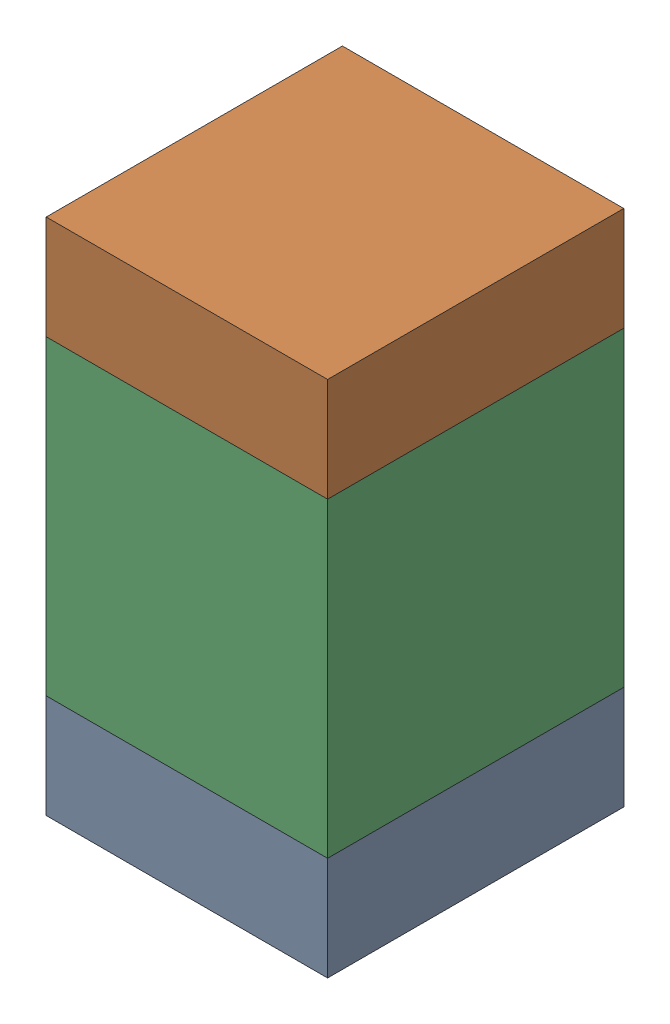
SolidWorks assembly C406PCB, configuration Default. Lengths in mm.
Overall size (0.95 1.75 1).
6 component instances, 2 part files, 0 mates.
Components (placement in the parent):
- 761616520-1: 761616520 [Default] at (87.3 124.8 0) size (0.95 0.35 1)
  - Extruded_6-1: Extruded_6 [Default] at origin size (0.95 0.35 1)
- 761616520-2: 761616520 [Default] at (87.3 126.2 0) size (0.95 0.35 1)
  - Extruded_6-1: Extruded_6 [Default] at origin size (0.95 0.35 1)
- 761616384-1: 761616384 [Default] at (87.3 125.5 0) size (0.95 1.05 1)
  - Extruded_5-1: Extruded_5 [Default] at origin size (0.95 1.05 1)
